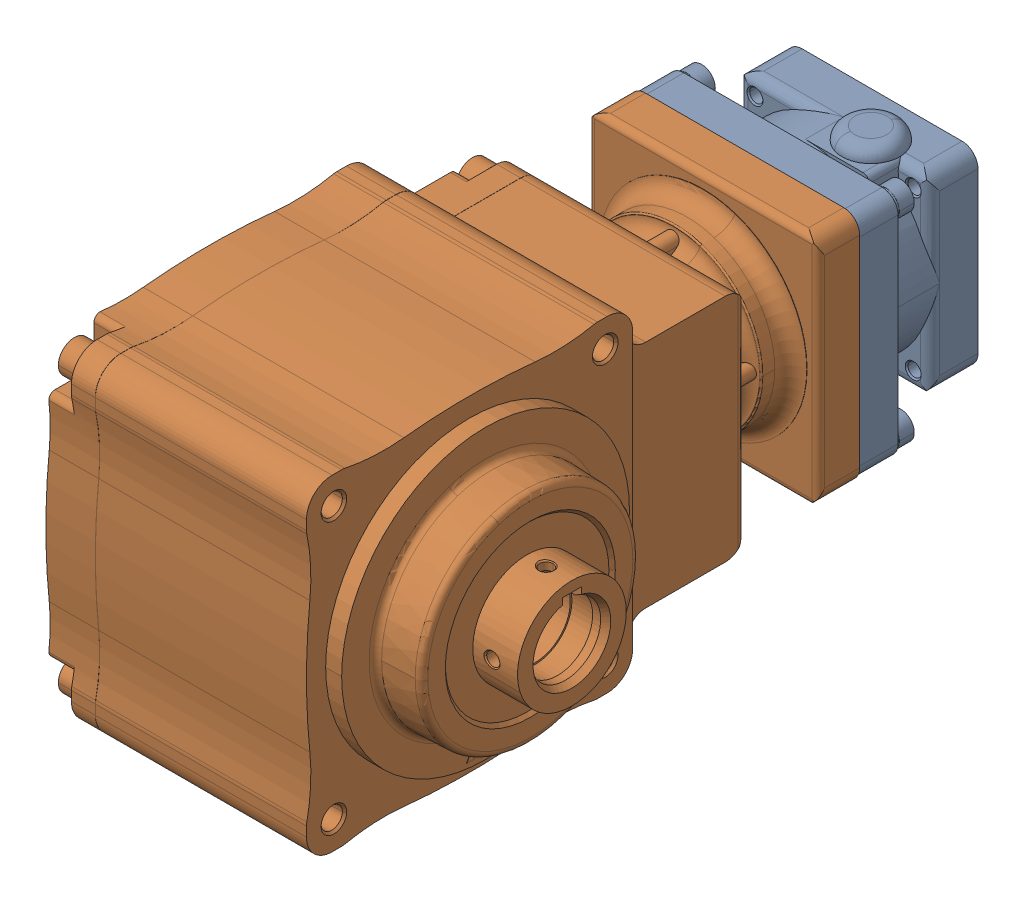
SolidWorks assembly AFCZ22S_50M200S2_None__oh, configuration Default. Lengths in mm.
Overall size (126 102.06 218.03).
2 component instances, 2 part files, 0 mates.
Components (placement in the parent):
- AFCZ22S_50M200S2_None__3_oh-1: AFCZ22S_50M200S2_None__3_oh [Default] at (0 0 -124) x (0 0 1) z (-1 0 0) size (43 72 72)
- AFCZ22S_50M200S2_None__5_oh-1: AFCZ22S_50M200S2_None__5_oh [Default] at (38 0 0) size (126 102.06 175.03)
